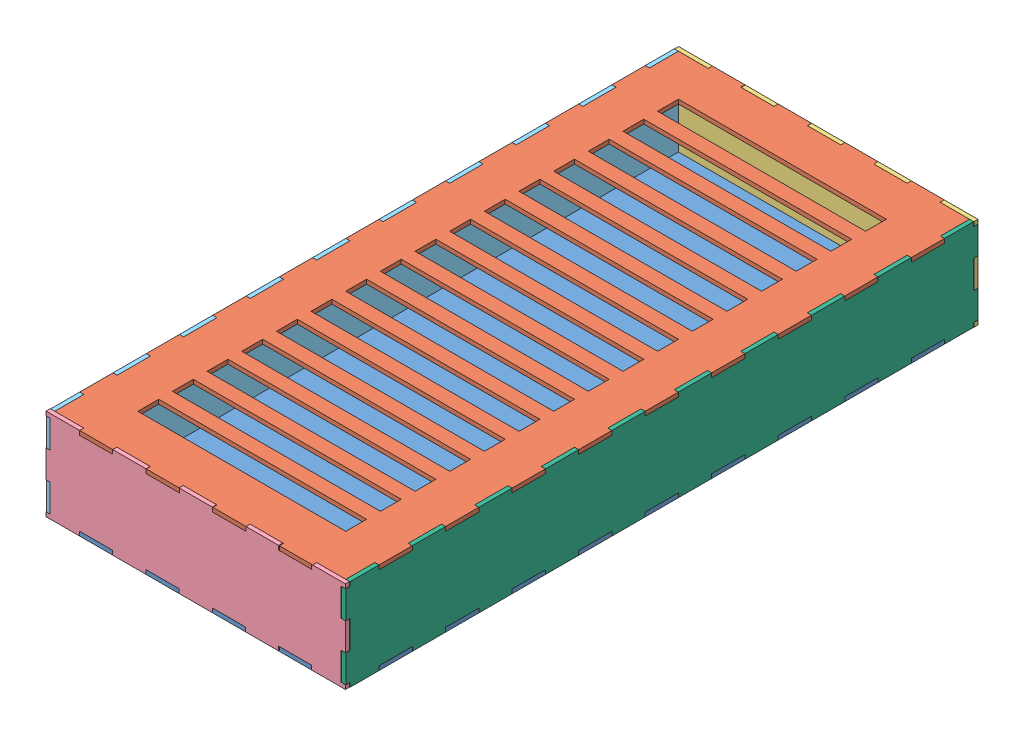
SolidWorks assembly Assem1, configuration Default. Lengths in mm.
Overall size (216.43 66 456).
6 component instances, 6 part files, 16 mates.
Components (placement in the parent):
- onderkant-1: onderkant [Default] at (-33.7944 8.8037 10.8327) size (216 3 456)
- bovenkant-2: bovenkant [Default] at (-33.7944 71.8037 10.8327) size (216 3 456)
- achterkant-1: achterkant [Default] at (-33.674 5.8037 -217.1673) size (216 66 3)
- voorkant-1: voorkant [Default] at (-34.1003 5.8037 235.8327) size (216 66 3)
- lange_zijkant1-1: lange_zijkant1 [Default] at (-138.7944 2.8037 10.8327) x (0 0 1) z (-1 0 0) size (456 66 3)
- lange_zijkant2-1: lange_zijkant2 [Default] at (71.2056 2.8037 10.8327) x (0 0 -1) z (1 0 0) size (456 66 3)
Mates (geometry in assembly coordinates):
- Parallel1: parallel anti-aligned: plane of onderkant-1 through (-33.7944 11.8037 10.8327) normal (0 1 0); plane of bovenkant-2 through (-33.7944 71.8037 10.8327) normal (0 -1 0)
- Coincident2: coincident anti-aligned: plane of onderkant-1 through (-138.7944 11.8037 -214.1673) normal (0 0 -1); plane of achterkant-1 through (-33.674 5.8037 -214.1673) normal (0 0 1)
- Coincident3: coincident anti-aligned: plane of bovenkant-2 through (-138.7944 74.8037 -214.1673) normal (0 0 -1); plane of achterkant-1 through (-33.674 5.8037 -214.1673) normal (0 0 1)
- Coincident4: coincident anti-aligned: plane of bovenkant-2 through (-33.7944 71.8037 10.8327) normal (0 -1 0); plane of achterkant-1 through (26.2056 71.8037 -214.1673) normal (0 1 0)
- Coincident5: coincident anti-aligned: plane of bovenkant-2 through (26.2056 71.8037 10.8327) normal (-1 0 0); plane of achterkant-1 through (26.2056 74.8037 -214.1673) normal (1 0 0)
- Coincident6: coincident anti-aligned: plane of onderkant-1 through (-33.7944 11.8037 10.8327) normal (0 1 0); plane of achterkant-1 through (2.1839 11.8037 -214.1673) normal (0 -1 0)
- Coincident7: coincident anti-aligned: plane of onderkant-1 through (26.2056 8.8037 10.8327) normal (-1 0 0); plane of achterkant-1 through (26.2056 11.8037 -214.1673) normal (1 0 0)
- Coincident8: coincident anti-aligned: plane of onderkant-1 through (-138.7944 11.8037 235.8327) normal (0 0 1); plane of voorkant-1 through (-34.1003 5.8037 235.8327) normal (0 0 -1)
- Coincident9: coincident anti-aligned: plane of bovenkant-2 through (-33.7944 71.8037 10.8327) normal (0 -1 0); plane of voorkant-1 through (-117.7944 71.8037 238.8327) normal (0 1 0)
- Coincident10: coincident anti-aligned: plane of bovenkant-2 through (-117.7944 71.8037 10.8327) normal (-1 0 0); plane of voorkant-1 through (-117.7944 74.8037 238.8327) normal (1 0 0)
- Coincident11: coincident anti-aligned: plane of bovenkant-2 through (-138.7944 74.8037 235.8327) normal (-1 0 0); plane of lange_zijkant1-1 through (-138.7944 2.8037 10.8327) normal (1 0 0)
- Coincident12: coincident anti-aligned: plane of voorkant-1 through (-34.1003 5.8037 235.8327) normal (0 0 -1); plane of lange_zijkant1-1 through (-141.7944 2.8037 235.8327) normal (0 0 1)
- Coincident13: coincident anti-aligned: plane of onderkant-1 through (-33.7944 11.8037 10.8327) normal (0 1 0); plane of lange_zijkant1-1 through (-141.7944 11.8037 10.8327) normal (0 -1 0)
- Coincident14: coincident: plane of bovenkant-2 through (71.2056 74.8037 235.8327) normal (1 0 0); plane of lange_zijkant2-1 through (71.2056 2.8037 10.8327) normal (-1 0 0)
- Coincident15: coincident: plane of voorkant-1 through (-34.1003 5.8037 235.8327) normal (0 0 -1); plane of lange_zijkant2-1 through (74.2056 2.8037 235.8327) normal (0 0 1)
- Coincident16: coincident anti-aligned: plane of onderkant-1 through (-33.7944 11.8037 10.8327) normal (0 1 0); plane of lange_zijkant2-1 through (74.2056 11.8037 10.8327) normal (0 -1 0)
